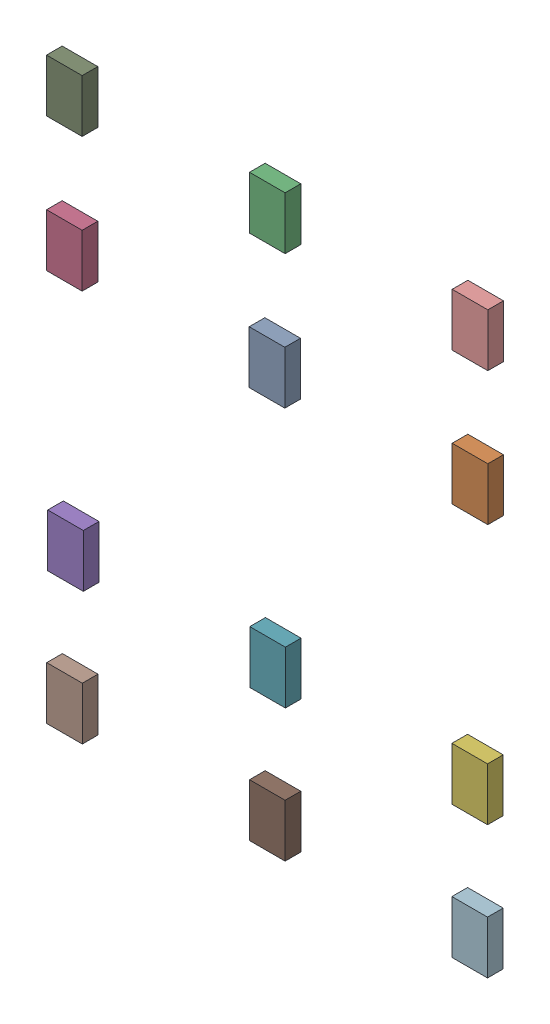
SolidWorks assembly Free-Models, configuration Default. Lengths in mm.
Overall size (92.9 121.84 3.3).
24 component instances, 1 part files, 0 mates.
Components (placement in the parent):
- 334789808-1: 334789808 [Default] at (88.836 137.16 0.1) size (7.5 11.1 3.3)
  - Extruded_20-1: Extruded_20 [Default] at origin size (7.5 11.1 3.3)
- 334789808-2: 334789808 [Default] at (131.568 137.287 0.1) size (7.5 11.1 3.3)
  - Extruded_20-1: Extruded_20 [Default] at origin size (7.5 11.1 3.3)
- 334789808-3: 334789808 [Default] at (88.9 165.354 0.1) size (7.5 11.1 3.3)
  - Extruded_20-1: Extruded_20 [Default] at origin size (7.5 11.1 3.3)
- 334789808-4: 334789808 [Default] at (46.17 137.16 0.1) size (7.5 11.1 3.3)
  - Extruded_20-1: Extruded_20 [Default] at origin size (7.5 11.1 3.3)
- 334789808-5: 334789808 [Default] at (46.423 82.55 0.1) size (7.5 11.1 3.3)
  - Extruded_20-1: Extruded_20 [Default] at origin size (7.5 11.1 3.3)
- 334789808-6: 334789808 [Default] at (131.513 82.55 0.1) size (7.5 11.1 3.3)
  - Extruded_20-1: Extruded_20 [Default] at origin size (7.5 11.1 3.3)
- 334789808-7: 334789808 [Default] at (88.959 82.55 0.1) size (7.5 11.1 3.3)
  - Extruded_20-1: Extruded_20 [Default] at origin size (7.5 11.1 3.3)
- 334789808-8: 334789808 [Default] at (46.212 54.61 0.1) size (7.5 11.1 3.3)
  - Extruded_20-1: Extruded_20 [Default] at origin size (7.5 11.1 3.3)
- 334789808-9: 334789808 [Default] at (46.169 165.354 0.1) size (7.5 11.1 3.3)
  - Extruded_20-1: Extruded_20 [Default] at origin size (7.5 11.1 3.3)
- 334789808-10: 334789808 [Default] at (131.572 165.354 0.1) size (7.5 11.1 3.3)
  - Extruded_20-1: Extruded_20 [Default] at origin size (7.5 11.1 3.3)
- 334789808-11: 334789808 [Default] at (88.9 54.61 0.1) size (7.5 11.1 3.3)
  - Extruded_20-1: Extruded_20 [Default] at origin size (7.5 11.1 3.3)
- 334789808-12: 334789808 [Default] at (131.508 54.61 0.1) size (7.5 11.1 3.3)
  - Extruded_20-1: Extruded_20 [Default] at origin size (7.5 11.1 3.3)
